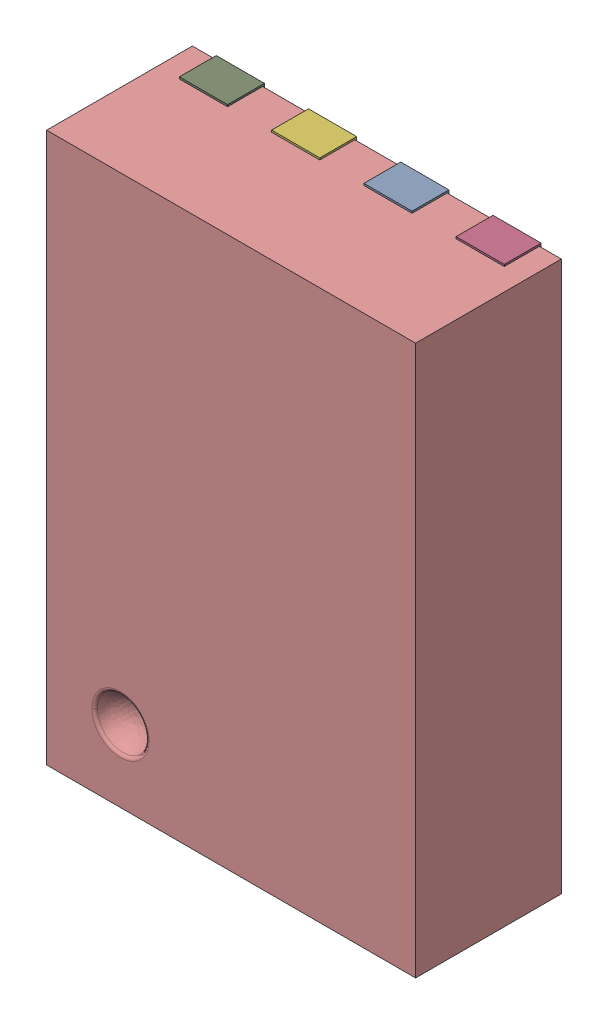
SolidWorks assembly U4, configuration Standard. Lengths in mm.
Overall size (2 3 0.83).
12 component instances, 10 part files, 0 mates.
Components (placement in the parent):
- User Library-TDFN-8-1-1: User Library-TDFN-8-1 [Standard] at (3.7499 -12.8001 0) x (1 0 0) z (0 0 1) size (2 3 0.83)
  - User Library-TDFN-8-1-subassembly-1-1: User Library-TDFN-8-1-subassembly-1 [Standard] at origin size (1.76 3 0.2)
    - User Library-TDFN-8-1_Fusion-1: User Library-TDFN-8-1_Fusion [Standard] at origin size (0.26 0.3 0.2)
    - User Library-TDFN-8-1_Fusion-1-1: User Library-TDFN-8-1_Fusion-1 [Standard] at origin size (0.26 0.3 0.2)
    - User Library-TDFN-8-1_Fusion-2-1: User Library-TDFN-8-1_Fusion-2 [Standard] at origin size (1.5 1.5 0.2)
    - User Library-TDFN-8-1_Fusion-3-1: User Library-TDFN-8-1_Fusion-3 [Standard] at origin size (0.26 0.3 0.2)
    - User Library-TDFN-8-1_Fusion-4-1: User Library-TDFN-8-1_Fusion-4 [Standard] at origin size (0.26 0.3 0.2)
    - User Library-TDFN-8-1_Fusion-5-1: User Library-TDFN-8-1_Fusion-5 [Standard] at origin size (0.26 0.3 0.2)
    - User Library-TDFN-8-1_Fusion-6-1: User Library-TDFN-8-1_Fusion-6 [Standard] at origin size (0.26 0.3 0.2)
    - User Library-TDFN-8-1_Fusion-7-1: User Library-TDFN-8-1_Fusion-7 [Standard] at origin size (0.26 0.3 0.2)
    - User Library-TDFN-8-1_Fusion-8-1: User Library-TDFN-8-1_Fusion-8 [Standard] at origin size (0.26 0.3 0.2)
  - User Library-TDFN-8-1_Fillet-1: User Library-TDFN-8-1_Fillet [Standard] at origin size (2 2.98 0.82)
